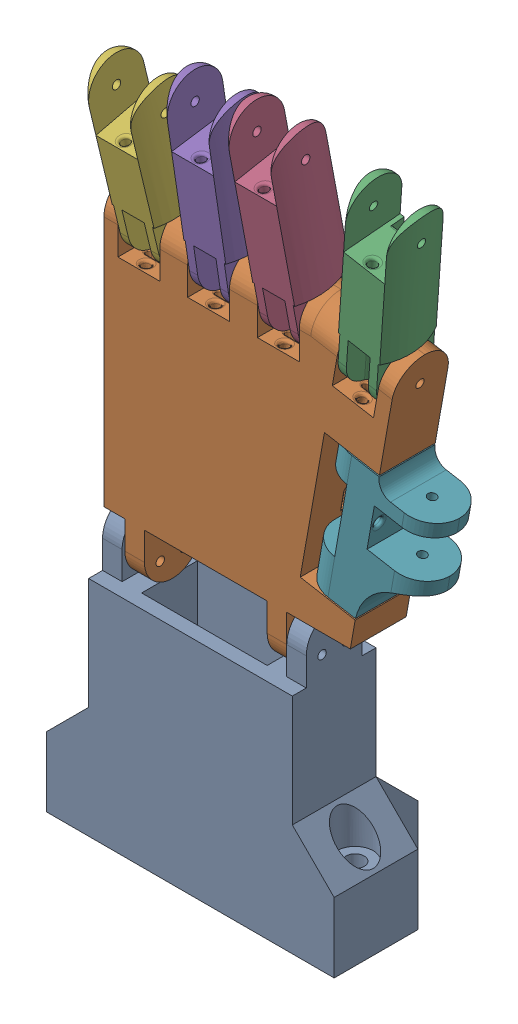
SolidWorks assembly Mano_sensores, configuration Default. Lengths in mm.
Overall size (133.83 255.73 52.55).
7 component instances, 7 part files, 17 mates.
Components (placement in the parent):
- Muneca-1: Muneca [Predeterminado] at origin size (103 100 45)
- Palma_sensores-1: Palma_sensores [Predeterminado] at (50.2512 150 5) size (105 120 20.95)
- Indice_Proximal_angle_sensor-1: Indice_Proximal_angle_sensor [Predeterminado] at (93.179 196.8192 16.1165) x (0.984808 -0.173648 0) z (0.172562 0.97865 0.111652) size (20 20 71)
- Medio_Proximal_angle_sensor-1: Medio_Proximal_angle_sensor [Predeterminado] at (63 199.8279 16.8473) x (1 0 0) z (0 0.98279 0.184727) size (20 20 76)
- Anular_Proximal_angle_sensor-1: Anular_Proximal_angle_sensor [Predeterminado] at (38 199.892 16.4658) x (1 0 0) z (0 0.989198 0.146583) size (20 20 71)
- Menique_Proximal_angle_sensor-1: Menique_Proximal_angle_sensor [Predeterminado] at (13 199.7244 17.3316) x (1 0 0) z (0 0.972439 0.233156) size (20 20 66)
- Pulgar_Proximal-1: Pulgar_Proximal [Predeterminado] at (70.9272 113.8134 5) x (0.984808 -0.173648 0) z (0 0 1) size (40 49 20)
Mates (geometry in assembly coordinates):
- Coincident1: coordinate: point of Muneca-1
- Coincident2: coincident anti-aligned: plane of Muneca-1 through (66 100 5) normal (-1 0 0); plane of Palma_sensores-1 through (66 80 25) normal (1 0 0)
- Concentric1: concentric anti-aligned: cylinder of Muneca-1 through (-7 95 15) axis (1 0 0) radius 1.5; cylinder of Palma_sensores-1 through (78 95 15) axis (-1 0 0) radius 1.5
- Concentric2: concentric anti-aligned: cylinder of Muneca-1 through (-7 87.5 19.3301) axis (1 0 0) radius 1.5; cylinder of Palma_sensores-1 through (78 87.5 19.3301) axis (-1 0 0) radius 1.5
- Concentric3: concentric anti-aligned: cylinder of Muneca-1 through (-7 87.5 10.6699) axis (1 0 0) radius 1.5; cylinder of Palma_sensores-1 through (78 87.5 10.6699) axis (-1 0 0) radius 1.5
- Distance1: distance = 0.5 mm anti-aligned: plane of Indice_Proximal_angle_sensor-1 through (83.028 179.5613 3.946) normal (-0.984808 0.173648 0); plane of Palma_sensores-1 through (82.3309 178.487 5) normal (0.984808 -0.173648 0)
- Concentric4: concentric anti-aligned: circle of Palma_sensores-1; circle of Indice_Proximal_angle_sensor-1
- Distance2: distance = 0.5 mm anti-aligned: plane of Medio_Proximal_angle_sensor-1 through (56 182.0194 3.3248) normal (-1 0 0); plane of Palma_sensores-1 through (55.5 180 5) normal (1 0 0)
- Concentric5: concentric aligned: cylinder of Palma_sensores-1 through (75.5 190 15) axis (-1 0 0) radius 1.5; cylinder of Medio_Proximal_angle_sensor-1 through (70 190 15) axis (-1 0 0) radius 1.5
- Distance3: distance = 0.5 mm anti-aligned: plane of Anular_Proximal_angle_sensor-1 through (31 181.5738 3.6422) normal (-1 0 0); plane of Palma_sensores-1 through (30.5 180 5) normal (1 0 0)
- Concentric6: concentric aligned: cylinder of Palma_sensores-1 through (75.5 190 15) axis (-1 0 0) radius 1.5; cylinder of Anular_Proximal_angle_sensor-1 through (45 190 15) axis (-1 0 0) radius 1.5
- Distance4: distance = 0.5 mm anti-aligned: plane of Menique_Proximal_angle_sensor-1 through (6 182.6072 2.944) normal (-1 0 0); plane of Palma_sensores-1 through (5.5 180 5) normal (1 0 0)
- Concentric7: concentric aligned: cylinder of Palma_sensores-1 through (75.5 190 15) axis (-1 0 0) radius 1.5; cylinder of Menique_Proximal_angle_sensor-1 through (20 190 15) axis (-1 0 0) radius 1.5
- Distance5: distance = 0.5 mm anti-aligned: plane of Pulgar_Proximal-1 through (79.4359 162.069 25) normal (0.173648 0.984808 0); plane of Palma_sensores-1 through (79.5228 162.5614 25) normal (-0.173648 -0.984808 0)
- Concentric8: concentric aligned: cylinder of Palma_sensores-1 through (90.2391 165.749 15) axis (-0.173648 -0.984808 0) radius 1.5; cylinder of Pulgar_Proximal-1 through (89.4577 161.3174 15) axis (-0.173648 -0.984808 0) radius 1.5
- LimitAngle1: limit planar angle = 3.141593 rad aligned: plane of Pulgar_Proximal-1 through (70.9272 113.8134 25) normal (-0.984808 0.173648 0); plane of Palma_sensores-1 through (76.492 145.373 5) normal (0.984808 -0.173648 0)
- LimitAngle2: limit planar angle = 3.141593 rad aligned: plane of Palma_sensores-1 through (56.0901 183.114 5) normal (0.173648 0.984808 0); plane of Indice_Proximal_angle_sensor-1 through (95.658 176.3252 3.8344) normal (-0.173648 -0.984808 0)
